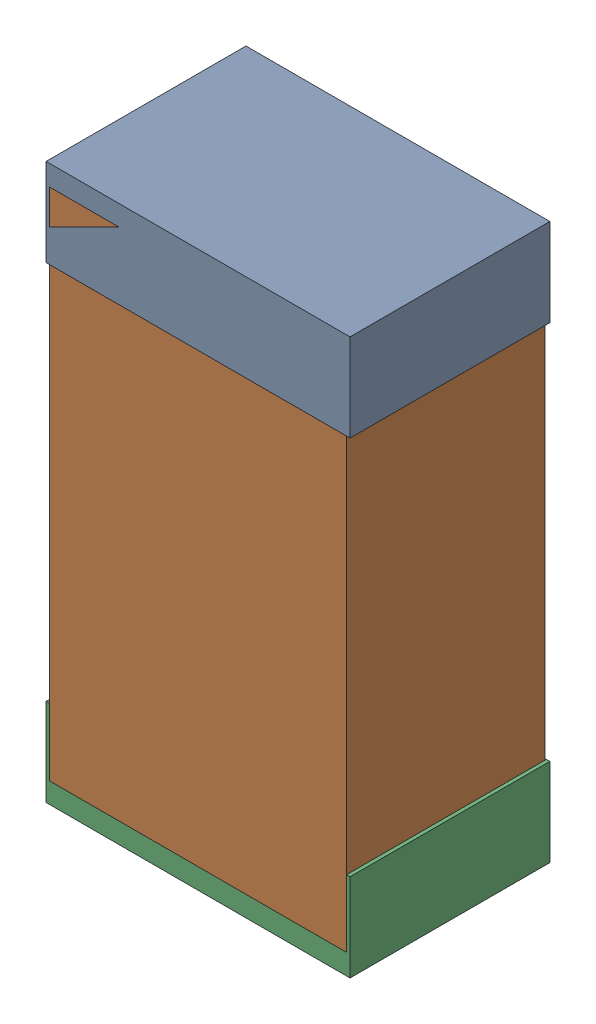
SolidWorks assembly R33Kanaloa_v2.0.0_Motor, configuration Default. Lengths in mm.
Overall size (1.3 2.38 0.85).
6 component instances, 2 part files, 0 mates.
Components (placement in the parent):
- 330415056-1: 330415056 [Default] at (124.714 95.175 -1.9574) size (1.3 0.38 0.85)
  - Extruded_2-1: Extruded_2 [Default] at origin size (1.3 0.38 0.85)
- 334787376-1: 334787376 [Default] at (124.714 94.175 -1.9524) size (1.27 2.2 0.85)
  - Extruded_16-1: Extruded_16 [Default] at origin size (1.27 2.2 0.85)
- 330415056-2: 330415056 [Default] at (124.714 93.175 -1.9574) size (1.3 0.38 0.85)
  - Extruded_2-1: Extruded_2 [Default] at origin size (1.3 0.38 0.85)
